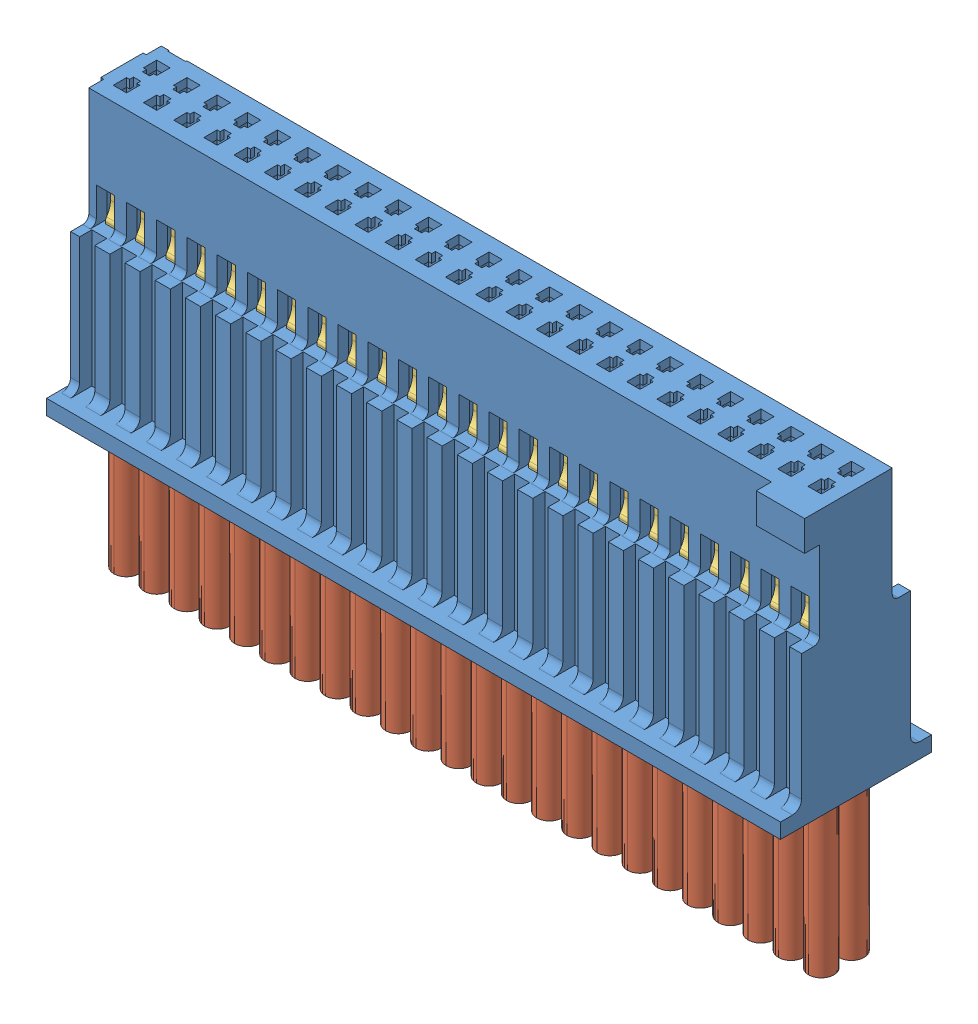
SolidWorks assembly SFSD_24_30C_G_15_00_S, configuration Default. Lengths in mm.
Overall size (30.86 17.53 6.35).
4 component instances, 3 part files, 0 mates.
Components (placement in the parent):
- _SFSD_24_30_S_b_2-1: _SFSD_24_30_S_b_2 [Default] at origin size (30.86 11.18 6.35)
- _SFSD_24_28_D_NUS_ca_4-1: _SFSD_24_28_D_NUS_ca_4 [Default] at origin size (30.28 7.11 2.34)
- _SFSD_24_p_6-1: _SFSD_24_p_6 [Default] at (-14.605 0.4572 0.2159) size (30.18 10.16 1.27)
- _SFSD_24_p_6-2: _SFSD_24_p_6 [Default] at (14.605 0.4572 -0.2159) x (-1 0 0) z (0 0 -1) size (30.18 10.16 1.27)
